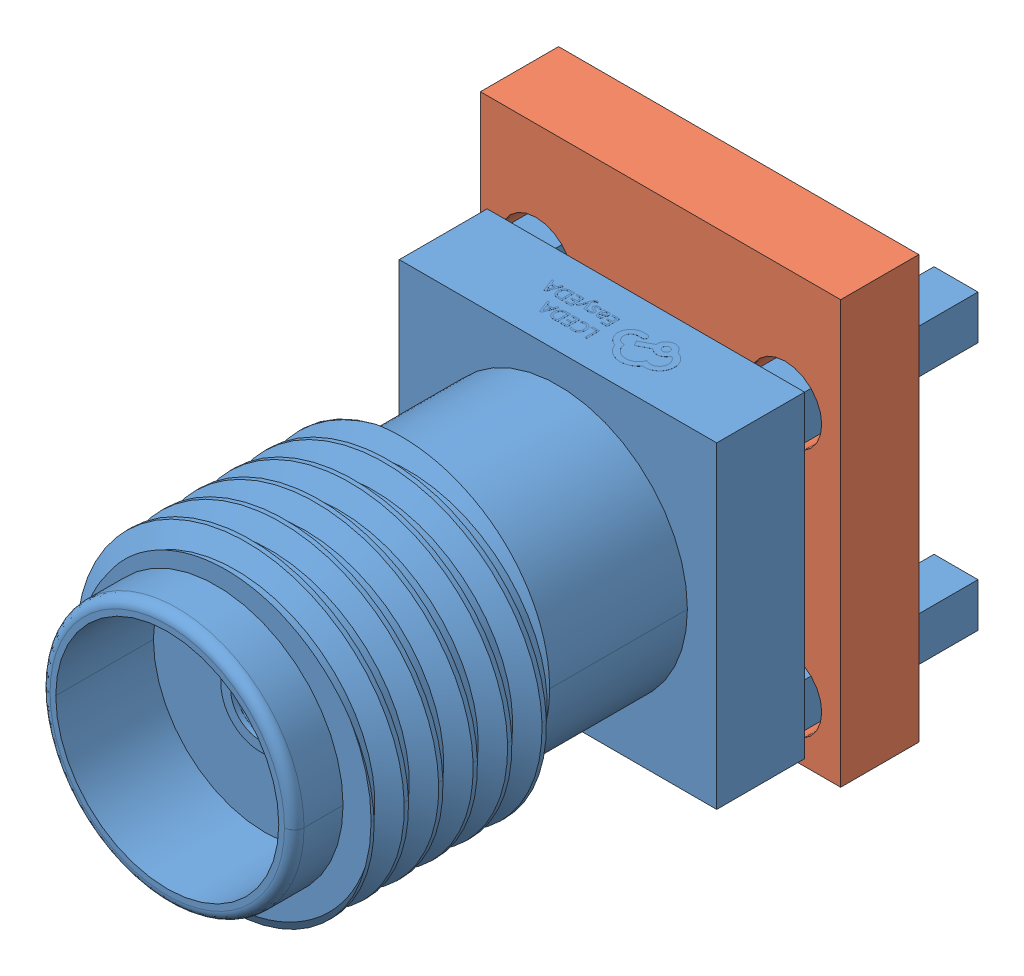
SolidWorks assembly 3D_PCB1_2023-12-02, configuration Standard. Lengths in mm.
Overall size (7.38 8.65 13.6).
5 component instances, 2 part files, 0 mates.
Components (placement in the parent):
- 3D_PCB1_2023-12-02.step-1: 3D_PCB1_2023-12-02.step [Standard] at origin size (7.38 8.65 13.6)
  - RF1.step-1: RF1.step [Standard] at (3.7008 -8.7008 1.6) size (6.5 7.33 13.6)
    - SMA-TH_BWSMA-KE-Z001.step-1: SMA-TH_BWSMA-KE-Z001.step [Standard] at origin size (6.5 7.33 13.6)
      - COMPOUND.step-1: COMPOUND.step [Standard] at origin size (6.5 7.33 13.6)
  - COMPOUND-0.step-1: COMPOUND-0.step [Standard] at origin size (7.38 8.65 1.6)
